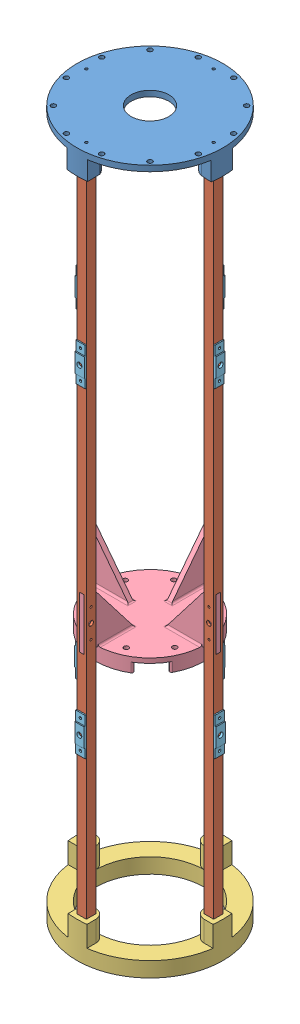
SolidWorks assembly v3LA_Assembly_V2, configuration Default. Lengths in mm.
Overall size (196.85 948.69 196.85).
15 component instances, 5 part files, 14 mates.
Components (placement in the parent):
- v3Top Ring correct-1: v3Top Ring correct [Default] at (64.066 124.7659 142.819) size (196.85 33.02 196.85)
- v3Stringer_V2-9: v3Stringer_V2 [Default] at (64.066 -338.7841 228.544) x (0 1 0) z (1 0 0) size (914.4 12.82 12.7)
- v3Stringer_V2-10: v3Stringer_V2 [Default] at (-21.659 -338.7841 142.819) x (0 1 0) z (0 0 1) size (914.4 12.82 12.7)
- v3Stringer_V2-11: v3Stringer_V2 [Default] at (64.066 -338.7841 57.094) x (0 1 0) z (-1 0 0) size (914.4 12.82 12.7)
- v3Stringer_V2-12: v3Stringer_V2 [Default] at (149.791 -338.7841 142.819) x (0 1 0) z (0 0 -1) size (914.4 12.82 12.7)
- v3Aft_Ring_V2_2-4: v3Aft_Ring_V2_2 [Default] at (64.066 -816.3041 142.819) x (1 0 0) z (0 0 1) size (196.85 48.26 196.85)
- v3DartThrust_3_2-7: v3DartThrust_3_2 [Default] at (64.066 -460.6947 142.819) size (184.27 88.9 184.27)
- v3LA-Spacers_v2-1: v3LA-Spacers_v2 [Default] at (156.0731 -137.9589 143.6967) x (0 0 -1) z (1 0 0) size (12.7 50.8 3.17)
- v3LA-Spacers_v2-9: v3LA-Spacers_v2 [Default] at (156.2017 -539.6093 141.9414) x (0 0 1) z (1 0 0) size (12.7 50.8 3.17)
- v3LA-Spacers_v2-10: v3LA-Spacers_v2 [Default] at (64.9437 -539.6093 234.9547) x (-1 0 0) z (0 0 1) size (12.7 50.8 3.17)
- v3LA-Spacers_v2-11: v3LA-Spacers_v2 [Default] at (-28.0696 -539.6093 143.6967) x (0 0 -1) z (-1 0 0) size (12.7 50.8 3.17)
- v3LA-Spacers_v2-12: v3LA-Spacers_v2 [Default] at (63.1884 -539.6093 50.6833) x (1 0 0) z (0 0 -1) size (12.7 50.8 3.17)
- v3LA-Spacers_v2-6: v3LA-Spacers_v2 [Default] at (63.1884 -137.9589 234.8261) size (12.7 50.8 3.17)
- v3LA-Spacers_v2-7: v3LA-Spacers_v2 [Default] at (-27.941 -137.9589 141.9414) x (0 0 1) z (-1 0 0) size (12.7 50.8 3.17)
- v3LA-Spacers_v2-8: v3LA-Spacers_v2 [Default] at (64.9437 -137.9589 50.8119) x (-1 0 0) z (0 0 -1) size (12.7 50.8 3.17)
Mates (geometry in assembly coordinates):
- Concentric14: concentric anti-aligned: cylinder of v3Top Ring correct-1 through (64.066 118.4159 228.544) axis (0 -1 0) radius 5.2578; cylinder of v3Stringer_V2-9 through (64.066 99.3659 228.544) axis (0 1 0) radius 5.334
- Concentric15: concentric aligned: cylinder of v3Stringer_V2-9 through (64.066 -768.0441 228.544) axis (0 -1 0) radius 5.334; cylinder of v3Aft_Ring_V2_2-4 through (64.066 -768.0441 228.544) axis (0 -1 0) radius 5.334
- Concentric16: concentric aligned: cylinder of v3Stringer_V2-12 through (149.791 -768.0441 142.819) axis (0 -1 0) radius 5.334; cylinder of v3Aft_Ring_V2_2-4 through (149.791 -768.0441 142.819) axis (0 -1 0) radius 5.334
- Coincident17: coincident anti-aligned: plane of v3Top Ring correct-1 through (64.066 118.4159 228.544) normal (0 -1 0); plane of v3Stringer_V2-9 through (64.066 118.4159 228.544) normal (0 1 0)
- Coincident18: coincident anti-aligned: plane of v3Stringer_V2-9 through (64.066 -795.9841 228.544) normal (0 -1 0); plane of v3Aft_Ring_V2_2-4 through (64.066 -795.9841 142.819) normal (0 1 0)
- Concentric20: concentric anti-aligned: cylinder of v3Top Ring correct-1 through (64.066 132.3859 142.819) axis (0 -1 0) radius 98.425; cylinder of v3DartThrust_3_2-7 through (64.066 -479.7447 142.819) axis (0 1 0) radius 73.025
- Parallel5: parallel aligned: cylinder of v3Stringer_V2-9 through (57.716 -425.7697 228.544) axis (1 0 0) radius 3.175; cylinder of v3DartThrust_3_2-7 through (60.891 -425.7697 228.6047) axis (1 0 0) radius 3.175
- Coincident26: coincident anti-aligned: plane of v3Stringer_V2-9 through (60.891 -460.6947 234.9547) normal (0 1 0); plane of v3DartThrust_3_2-7 through (60.891 -460.6947 168.2797) normal (0 -1 0)
- Coincident27: coincident aligned: plane of v3Stringer_V2-9 through (70.416 118.4159 234.9547) normal (0 0 1); plane of v3DartThrust_3_2-7 through (60.891 -460.6947 234.9547) normal (0 0 1)
- Concentric24: concentric anti-aligned: cylinder of v3Stringer_V2-12 through (143.3794 -122.8841 142.819) axis (1 0 0) radius 3.175; cylinder of LA-Spacers_v2-1 through (159.2481 -122.8841 142.819) axis (-1 0 0) radius 3.3782
- Coincident28: coincident anti-aligned: plane of v3Stringer_V2-12 through (156.2017 118.4159 136.469) normal (1 0 0); plane of v3LA-Spacers_v2-9 through (156.2017 -539.6093 141.9414) normal (-1 0 0)
- Concentric27: concentric anti-aligned: cylinder of v3Stringer_V2-12 through (145.2797 -573.7341 142.819) axis (1 0 0) radius 1.4224; cylinder of v3LA-Spacers_v2-9 through (159.3767 -573.7341 142.819) axis (-1 0 0) radius 1.632
- Concentric28: concentric anti-aligned: cylinder of v3Stringer_V2-12 through (143.3794 -554.6841 142.819) axis (1 0 0) radius 3.175; cylinder of v3LA-Spacers_v2-9 through (159.3767 -554.6841 142.819) axis (-1 0 0) radius 3.3782
- Concentric29: concentric anti-aligned: cylinder of v3Stringer_V2-12 through (145.2797 -103.8341 142.819) axis (1 0 0) radius 1.4224; cylinder of v3LA-Spacers_v2-1 through (159.2481 -103.8341 142.819) axis (-1 0 0) radius 1.632
